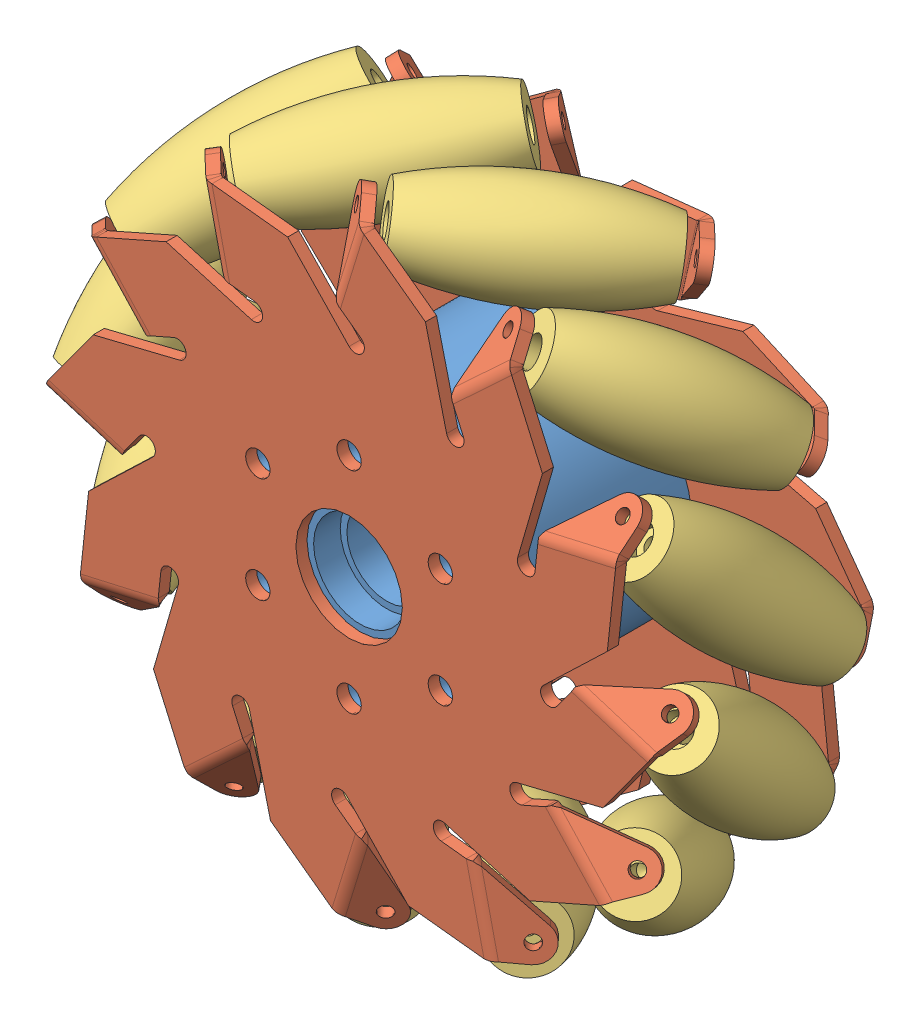
SolidWorks assembly Mecanum-Wheel, configuration Default. Lengths in mm.
Overall size (164.78 164.78 53.84).
15 component instances, 3 part files, 11 mates.
Components (placement in the parent):
- Verbindungsstück-1: Verbindungsstück [Default] at origin size (60 60 45)
- Blechbiegeteil-1: Blechbiegeteil [Default] at origin size (142.69 142.69 9.8)
- Blechbiegeteil-2: Blechbiegeteil [Default] at (0 0 45) x (-1 0 0) z (0 0 -1) size (142.69 142.69 9.8)
- Roller-1: Roller [Default] at (0.6237 65.9932 39.8219) x (0.689366 -0.157398 -0.707107) z (0.723507 0.198412 0.661189) size (47.5 22.21 22.21)
- Roller-2: Roller [Default] at (-32.4565 57.4637 39.8219) x (0.675708 0.208372 -0.707107) z (0.527369 0.533583 0.661189) size (47.5 22.21 22.21)
- Roller-3: Roller [Default] at (-56.8399 33.5368 39.8219) x (0.480994 0.51831 -0.707107) z (0.189923 0.725781 0.661189) size (47.5 22.21 22.21)
- Roller-4: Roller [Default] at (-65.9932 0.6237 39.8219) x (0.157398 0.689366 -0.707107) z (-0.198412 0.723507 0.661189) size (47.5 22.21 22.21)
- Roller-5: Roller [Default] at (-57.4637 -32.4565 39.8219) x (-0.208372 0.675708 -0.707107) z (-0.533583 0.527369 0.661189) size (47.5 22.21 22.21)
- Roller-6: Roller [Default] at (-33.5368 -56.8399 39.8219) x (-0.51831 0.480994 -0.707107) z (-0.725781 0.189923 0.661189) size (47.5 22.21 22.21)
- Roller-7: Roller [Default] at (-0.6237 -65.9932 39.8219) x (-0.689366 0.157398 -0.707107) z (-0.723507 -0.198412 0.661189) size (47.5 22.21 22.21)
- Roller-8: Roller [Default] at (32.4565 -57.4637 39.8219) x (-0.675708 -0.208372 -0.707107) z (-0.527369 -0.533583 0.661189) size (47.5 22.21 22.21)
- Roller-9: Roller [Default] at (56.8399 -33.5368 39.8219) x (-0.480994 -0.51831 -0.707107) z (-0.189923 -0.725781 0.661189) size (47.5 22.21 22.21)
- Roller-10: Roller [Default] at (65.9932 -0.6237 39.8219) x (-0.157398 -0.689366 -0.707107) z (0.198412 -0.723507 0.661189) size (47.5 22.21 22.21)
- Roller-11: Roller [Default] at (57.4637 32.4565 39.8219) x (0.208372 -0.675708 -0.707107) z (0.533583 -0.527369 0.661189) size (47.5 22.21 22.21)
- Roller-12: Roller [Default] at (33.5368 56.8399 39.8219) x (0.51831 -0.480994 -0.707107) z (0.725781 -0.189923 0.661189) size (47.5 22.21 22.21)
Mates (geometry in assembly coordinates):
- Coincident1: coincident aligned: plane of Verbindungsstück-1 through (0 0 0) normal (0 0 1)
- Coincident2: coincident aligned: plane of Verbindungsstück-1 through (0 0 0) normal (0 1 0)
- Coincident3: coincident aligned: plane of Verbindungsstück-1 through (0 0 0) normal (1 0 0)
- Concentric1: concentric aligned: cylinder of Verbindungsstück-1 through (0 0 45) axis (0 0 -1) radius 30; cylinder of Blechbiegeteil-1 through (0 0 7.296) axis (0 0 -1) radius 12
- Coincident4: coincident anti-aligned: plane of Verbindungsstück-1 through (0 0 0) normal (0 0 -1); plane of Blechbiegeteil-1 through (-1.4433 46.3845 0) normal (0 0 1)
- Concentric2: concentric anti-aligned: cylinder of Verbindungsstück-1 through (-20.5681 11.875 45) axis (0 0 1) radius 2.75; cylinder of Blechbiegeteil-1 through (-20.5681 11.875 -2.5) axis (0 0 -1) radius 2.75
- Concentric3: concentric anti-aligned: cylinder of Verbindungsstück-1 through (0 0 45) axis (0 0 -1) radius 30; cylinder of Blechbiegeteil-2 through (0 0 37.704) axis (0 0 1) radius 12
- Coincident5: coincident anti-aligned: plane of Verbindungsstück-1 through (0 0 45) normal (0 0 1); plane of Blechbiegeteil-2 through (1.4433 46.3845 45) normal (0 0 -1)
- Concentric4: concentric aligned: cylinder of Verbindungsstück-1 through (0 23.75 45) axis (0 0 1) radius 2.75; cylinder of Blechbiegeteil-2 through (0 23.75 47.5) axis (0 0 1) radius 2.75
- Concentric5: concentric anti-aligned: cylinder of Blechbiegeteil-1 through (36.8154 57.7298 2.6988) axis (-0.689366 0.157398 0.707107) radius 1.5; cylinder of Roller-1 through (33.3686 58.5168 6.2343) axis (0.689366 -0.157398 -0.707107) radius 3.25
- Distance1: distance = 2.5 mm anti-aligned: plane of Blechbiegeteil-1 through (6.051 44.6734 -20.852) normal (-0.689366 0.157398 0.707107); plane of Roller-1 through (33.0969 65.7723 4.3544) normal (0.689366 -0.157398 -0.707107)
